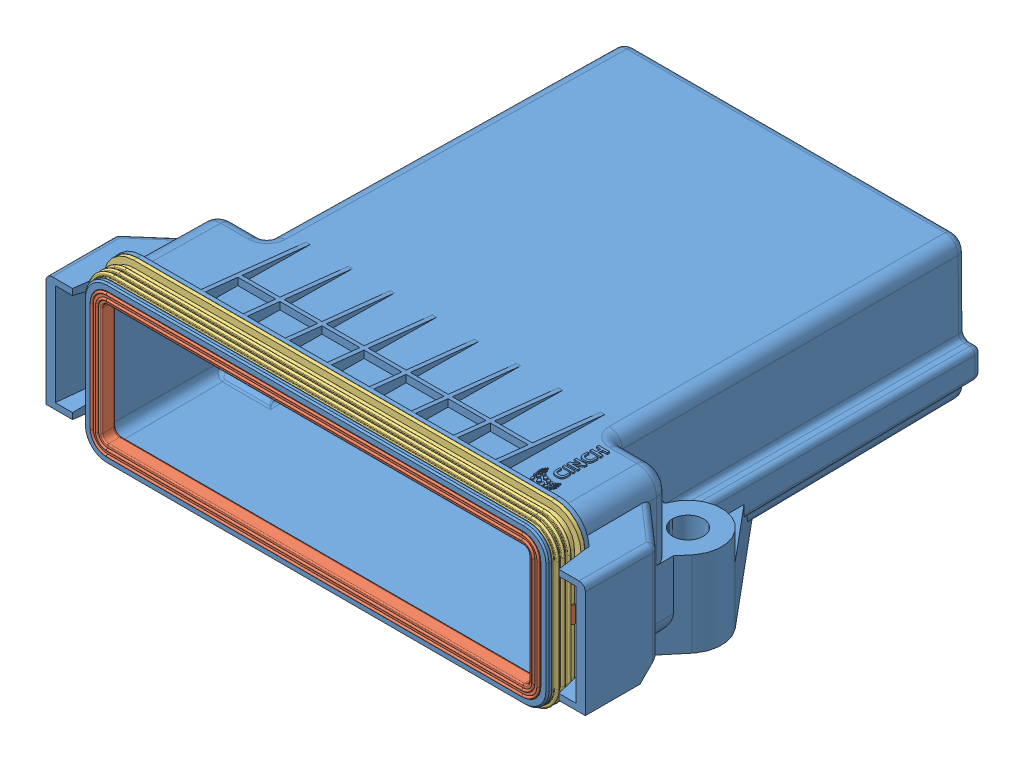
SolidWorks assembly 5810130065_rev_B, configuration Default. Lengths in mm.
Overall size (130.26 42.29 116.81).
4 component instances, 3 part files, 0 mates.
Components (placement in the parent):
- 5810130065_rev_B.stp-1: 5810130065_rev_B.stp [Default] at origin size (130.26 42.29 116.81)
  - 4828770226.stp-1: 4828770226.stp [Default] at origin size (130.26 42.29 116.81)
  - 4630899185_STRETCHED.stp-1: 4630899185_STRETCHED.stp [Default] at (0 0 2.54) size (112.73 38.37 7.62)
  - 4630899186_STRETCHED.stp-1: 4630899186_STRETCHED.stp [Default] at (0 0 -3.81) size (115.27 41.17 6.3)
